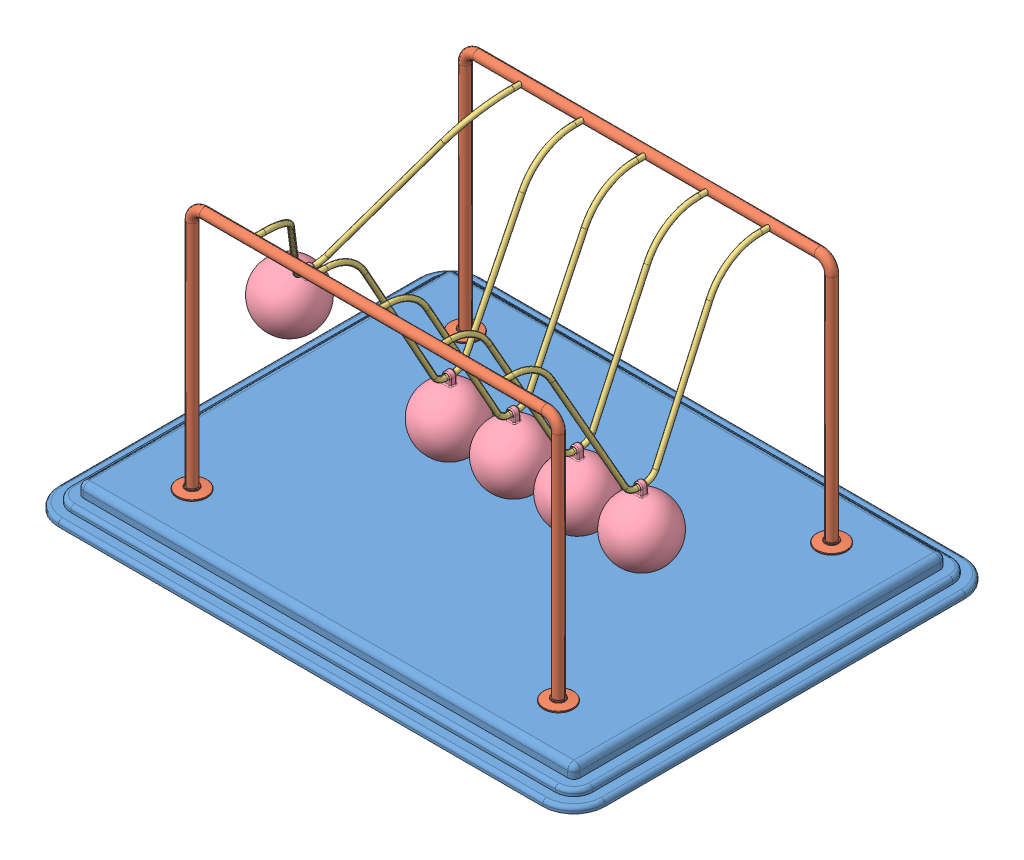
SolidWorks assembly Newtons Cradle NewtonsCradle 0248, configuration Default. Lengths in mm.
Overall size (440 222 340).
13 component instances, 4 part files, 34 mates.
Components (placement in the parent):
- Base 200,97244732577-1: Base 200,97244732577 [Default] at (-16.2968 -4.1587 11.425) size (440 20 340)
- frame NewtonsCradle 0248-1: frame NewtonsCradle 0248 [Default] at (-16.2968 144.4547 -98.575) size (319 202 24)
- frame NewtonsCradle 0248-2: frame NewtonsCradle 0248 [Default] at (-16.2968 144.4547 121.425) x (-1 0 0) z (0 0 -1) size (319 202 24)
- Hanging thing NewtonsCradle 0248-1: Hanging thing NewtonsCradle 0248 [Default] at (-157.6326 134.1825 11.425) x (0 0 1) z (-0.859985 0.510319 0) size (220 129 4)
- Hanging thing NewtonsCradle 0248-2: Hanging thing NewtonsCradle 0248 [Default] at (-66.576 122.8418 11.425) x (0 0 1) z (-0.999994 0.003446 0) size (220 129 4)
- Hanging thing NewtonsCradle 0248-3: Hanging thing NewtonsCradle 0248 [Default] at (-15.6923 122.8436 11.425) x (0 0 1) z (-0.999972 -0.007464 0) size (220 129 4)
- Hanging thing NewtonsCradle 0248-4: Hanging thing NewtonsCradle 0248 [Default] at (35.2213 122.8555 11.425) x (0 0 1) z (-0.999824 -0.018742 0) size (220 129 4)
- Hanging thing NewtonsCradle 0248-5: Hanging thing NewtonsCradle 0248 [Default] at (86.0287 122.8747 11.425) x (0 0 1) z (-0.999588 -0.028711 0) size (220 129 4)
- Sphere NewtonsCradle 0248-1: Sphere NewtonsCradle 0248 [Default] at (-195.3962 70.5436 11.425) x (0.859985 -0.510319 0) z (0 0 1) size (50 58.5 50)
- Sphere NewtonsCradle 0248-2: Sphere NewtonsCradle 0248 [Default] at (88.1533 48.9052 11.425) x (0.999588 0.028711 0) z (0 0 1) size (50 58.5 50)
- Sphere NewtonsCradle 0248-3: Sphere NewtonsCradle 0248 [Default] at (-15.14 48.8456 11.425) x (0.999972 0.007464 0) z (0 0 1) size (50 58.5 50)
- Sphere NewtonsCradle 0248-4: Sphere NewtonsCradle 0248 [Default] at (36.6081 48.8685 11.425) x (0.999824 0.018742 0) z (0 0 1) size (50 58.5 50)
- Sphere NewtonsCradle 0248-5: Sphere NewtonsCradle 0248 [Default] at (-66.831 48.8422 11.425) x (0.999994 -0.003446 0) z (0 0 1) size (50 58.5 50)
Mates (geometry in assembly coordinates):
- Coincident1: coincident anti-aligned: plane of Base-1 through (-211.2968 5.8413 156.425) normal (0 1 0); plane of frame-2 through (-175.7968 5.8413 121.425) normal (0 -1 0)
- Coincident2: coincident anti-aligned: plane of Base-1 through (-211.2968 5.8413 156.425) normal (0 1 0); plane of frame-1 through (143.2032 5.8413 -98.575) normal (0 -1 0)
- Concentric1: concentric anti-aligned: cylinder of frame-1 through (-116.2968 203.8413 -94.575) axis (0 0 -1) radius 2; cylinder of frame-2 through (-116.2968 203.8413 117.425) axis (0 0 1) radius 2
- Concentric2: concentric anti-aligned: cylinder of frame-1 through (83.7032 203.8413 -94.575) axis (0 0 -1) radius 2; cylinder of frame-2 through (83.7032 203.8413 117.425) axis (0 0 1) radius 2
- Distance1: distance = 60 mm: plane of frame-1 through (-16.2968 144.4547 -98.575) normal (0 0 1); line of Base-1 through (-211.2968 -12.1587 -158.575) axis (1 0 0)
- Distance2: distance = 60 mm: line of Base-1 through (178.7032 -12.1587 181.425) axis (-1 0 0); plane of frame-2 through (-16.2968 144.4547 121.425) normal (0 0 -1)
- Distance3: distance = 220 mm: plane of frame-2 through (-16.2968 144.4547 121.425) normal (-1 0 0); line of Base-1 through (-236.2968 -12.1587 156.425) axis (0 0 -1)
- Concentric3: concentric anti-aligned: cylinder of frame-1 through (-116.2968 203.8413 -94.575) axis (0 0 -1) radius 2; cylinder of Hanging thing-1 through (-116.2968 203.8413 111.425) axis (0 0 1) radius 2
- Concentric4: concentric anti-aligned: cylinder of frame-1 through (-116.2968 203.8413 -94.575) axis (0 0 -1) radius 2; cylinder of Hanging thing-1 through (-116.2968 203.8413 -98.575) axis (0 0 1) radius 2
- Concentric5: concentric aligned: cylinder of frame-2 through (-66.2968 203.8413 117.425) axis (0 0 1) radius 2; cylinder of Hanging thing-2 through (-66.2968 203.8413 111.425) axis (0 0 1) radius 2
- Concentric6: concentric aligned: cylinder of frame-2 through (-16.2968 203.8413 117.425) axis (0 0 1) radius 2; cylinder of Hanging thing-3 through (-16.2968 203.8413 111.425) axis (0 0 1) radius 2
- Concentric7: concentric aligned: cylinder of frame-2 through (33.7032 203.8413 117.425) axis (0 0 1) radius 2; cylinder of Hanging thing-4 through (33.7032 203.8413 111.425) axis (0 0 1) radius 2
- Concentric8: concentric aligned: cylinder of frame-2 through (83.7032 203.8413 117.425) axis (0 0 1) radius 2; cylinder of Hanging thing-5 through (83.7032 203.8413 111.425) axis (0 0 1) radius 2
- Coincident5: coincident anti-aligned: plane of frame-2 through (83.7032 203.8413 121.425) normal (0 0 -1); plane of Hanging thing-5 through (83.7032 203.8413 121.425) normal (0 0 1)
- Coincident6: coincident anti-aligned: plane of frame-2 through (33.7032 203.8413 121.425) normal (0 0 -1); plane of Hanging thing-4 through (33.7032 203.8413 121.425) normal (0 0 1)
- Coincident7: coincident anti-aligned: plane of frame-2 through (-16.2968 203.8413 121.425) normal (0 0 -1); plane of Hanging thing-3 through (-16.2968 203.8413 121.425) normal (0 0 1)
- Coincident8: coincident anti-aligned: plane of frame-2 through (-66.2968 203.8413 121.425) normal (0 0 -1); plane of Hanging thing-2 through (-66.2968 203.8413 121.425) normal (0 0 1)
- Coincident9: coincident anti-aligned: plane of frame-2 through (-116.2968 203.8413 121.425) normal (0 0 -1); plane of Hanging thing-1 through (-116.2968 203.8413 121.425) normal (0 0 1)
- Concentric9: concentric anti-aligned: cylinder of Hanging thing-1 through (-117.0163 78.8434 7.925) axis (0 0 1) radius 2; cylinder of Sphere-1 through (-117.0163 78.8434 13.925) axis (0 0 -1) radius 2
- Concentric13: concentric anti-aligned: cylinder of Hanging thing-2 through (-66.7276 78.842 7.925) axis (0 0 1) radius 2; cylinder of Sphere-5 through (-66.7276 78.842 13.925) axis (0 0 -1) radius 2
- Concentric15: concentric anti-aligned: cylinder of Hanging thing-3 through (-15.3639 78.8448 7.925) axis (0 0 1) radius 2; cylinder of Sphere-3 through (-15.3639 78.8448 13.925) axis (0 0 -1) radius 2
- Concentric16: concentric anti-aligned: cylinder of Hanging thing-5 through (87.292 78.8928 7.925) axis (0 0 1) radius 2; cylinder of Sphere-2 through (87.292 78.8928 13.925) axis (0 0 -1) radius 2
- Concentric17: concentric anti-aligned: cylinder of Hanging thing-4 through (36.0459 78.8632 7.925) axis (0 0 1) radius 2; cylinder of Sphere-4 through (36.0459 78.8632 13.925) axis (0 0 -1) radius 2
- Parallel1: parallel anti-aligned: plane of Hanging thing-1; plane of Sphere-1
- Coincident22: coincident anti-aligned: plane of Hanging thing-1; plane of Sphere-1
- Coincident12: coincident aligned: plane of Hanging thing-2 through (-66.576 122.8418 11.425) normal (0 0 1); plane of Sphere-5 through (-66.831 48.8422 11.425) normal (0 0 1)
- Coincident10: coincident aligned: plane of Hanging thing-1 through (-116.763 122.8426 11.425) normal (0 0 1); plane of Sphere-1 through (-118.5806 48.8842 11.425) normal (0 0 1)
- Coincident13: coincident anti-aligned: plane of Hanging thing-2 through (-66.576 122.8418 11.425) normal (-0.999994 0.003446 0); plane of Sphere-5 through (-66.831 48.8422 11.425) normal (0.999994 -0.003446 0)
- Coincident14: coincident anti-aligned: plane of Hanging thing-3 through (-15.6923 122.8436 11.425) normal (-0.999972 -0.007464 0); plane of Sphere-3 through (-15.14 48.8456 11.425) normal (0.999972 0.007464 0)
- Coincident15: coincident aligned: plane of Hanging thing-3 through (-15.6923 122.8436 11.425) normal (0 0 1); plane of Sphere-3 through (-15.14 48.8456 11.425) normal (0 0 1)
- Coincident18: coincident aligned: plane of Hanging thing-4 through (35.2213 122.8555 11.425) normal (0 0 1); plane of Sphere-4 through (36.6081 48.8685 11.425) normal (0 0 1)
- Coincident19: coincident anti-aligned: plane of Hanging thing-4 through (35.2213 122.8555 11.425) normal (-0.999824 -0.018742 0); plane of Sphere-4 through (36.6081 48.8685 11.425) normal (0.999824 0.018742 0)
- Coincident20: coincident anti-aligned: plane of Hanging thing-5 through (86.0287 122.8747 11.425) normal (-0.999588 -0.028711 0); plane of Sphere-2 through (88.1533 48.9052 11.425) normal (0.999588 0.028711 0)
- Coincident21: coincident aligned: plane of Hanging thing-5 through (86.0287 122.8747 11.425) normal (0 0 1); plane of Sphere-2 through (88.1533 48.9052 11.425) normal (0 0 1)
